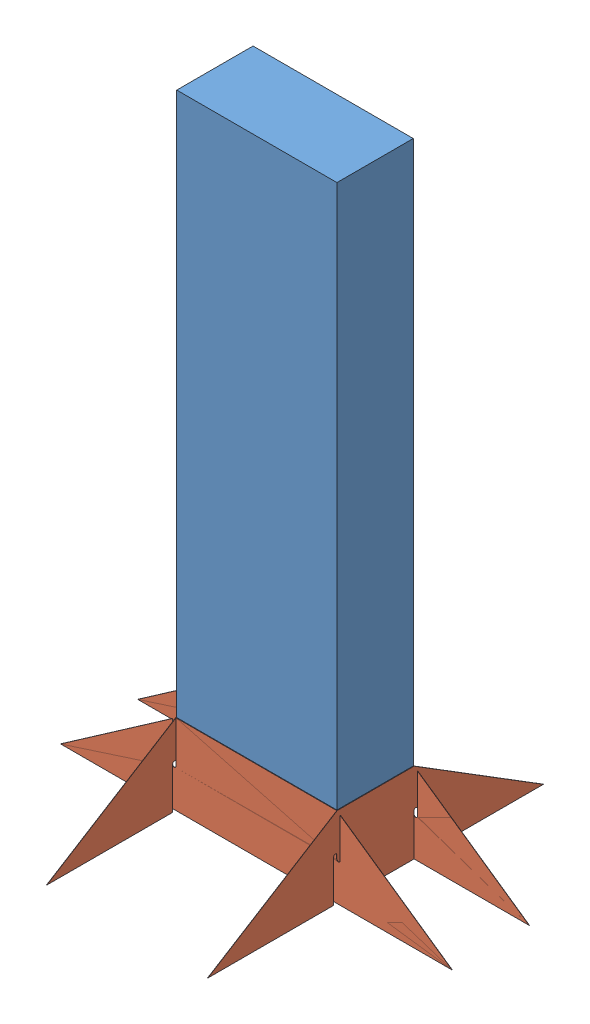
SolidWorks assembly base assembly, configuration Default. Lengths in mm.
Overall size (355.6 566.74 304.8).
7 component instances, 2 part files, 6 mates.
Components (placement in the parent):
- stage1-1: stage1 [Default] at origin size (146.05 566.74 69.85)
- base1-1: base1 [short side] at (73.025 0 0) x (0 0 -1) z (1 0 0) size (304.8 73.03 0.25)
- base1-2: base1 [long side] at (0 0 34.925) size (355.6 73.03 0.25)
- base1-3: base1 [long side] at (0 0 -35.179) size (355.6 73.03 0.25)
- base1-4: base1 [long side] at (0 0 35.179) x (-1 0 0) z (0 0 -1) size (355.6 73.03 0.25)
- base1-5: base1 [long side] at (0 0 -34.925) x (-1 0 0) z (0 0 -1) size (355.6 73.03 0.25)
- base1-6: base1 [short side] at (-73.279 0 0) x (0 0 -1) z (1 0 0) size (304.8 73.03 0.25)
Mates (geometry in assembly coordinates):
- Coincident1: coincident aligned: plane of base1-1; plane of assembly through (0 0 0) normal (0 1 0)
- Coincident2: coincident aligned: plane of stage1-1 through (73.025 73.025 34.925) normal (1 0 0); plane of base1-1 through (73.025 0 0) normal (1 0 0)
- Coincident3: coincident anti-aligned: plane of base1-1 through (73.025 0 0) normal (0 0 -1); plane of assembly through (0 0 0) normal (0 0 1)
- Coincident4: coincident aligned: plane of stage1-1 through (73.025 73.025 34.925) normal (0 0 1); plane of base1-2 through (0 0 34.925) normal (0 0 1)
- Coincident5: coincident aligned: plane of base1-2 through (0 0 34.925) normal (0 1 0); plane of assembly through (0 0 0) normal (0 1 0)
- Coincident6: coincident aligned: plane of base1-2 through (0 0 34.925) normal (1 0 0); plane of assembly through (0 0 0) normal (1 0 0)
